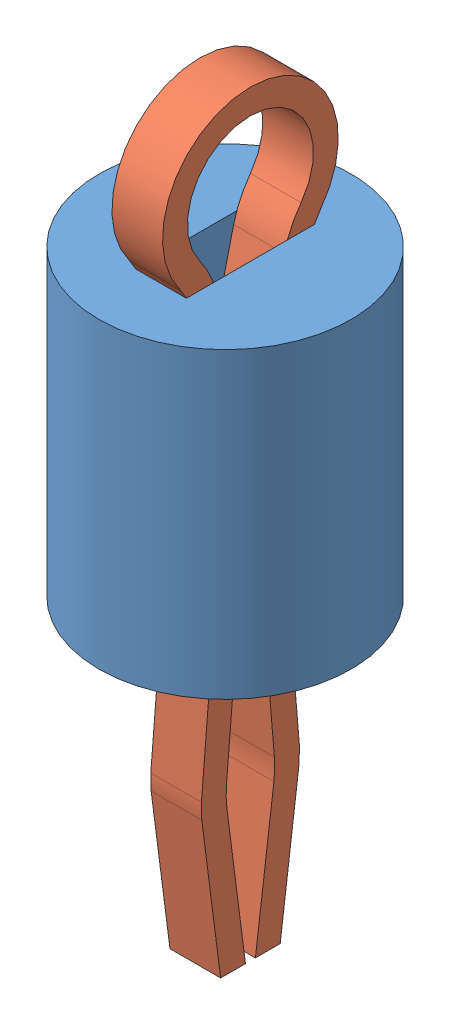
SolidWorks assembly Assem1, configuration Default. Lengths in mm.
Overall size (2.54 7.62 2.54).
2 component instances, 2 part files, 6 mates.
Components (placement in the parent):
- Spacer-yellow-1: Spacer-yellow [Default] x (0 0 1) z (0 1 0) size (2.54 2.54 3.05)
- Contact-1: Contact [Default] x (0 0 1) z (0 1 0) size (1.77 0.51 7.62)
Mates (geometry in assembly coordinates):
- Coincident1: coincident aligned: plane of Spacer-yellow-1 through (0 0 0) normal (1 0 0)
- Coincident2: coincident aligned: plane of Spacer-yellow-1 through (0 0 0) normal (0 0 1)
- Coincident3: coincident anti-aligned: plane of Spacer-yellow-1 through (0 0 0) normal (0 -1 0)
- Coincident4: coincident aligned: plane of Contact-1 through (0 0 0) normal (1 0 0)
- Coincident5: coincident aligned: plane of Contact-1 through (0 0 0) normal (0 0 1)
- Distance1: distance = 3.05 mm aligned: plane of Spacer-yellow-1 through (0 0 0) normal (0 -1 0); plane of Contact-1 through (0 -3.05 0.175) normal (0 -1 0)
